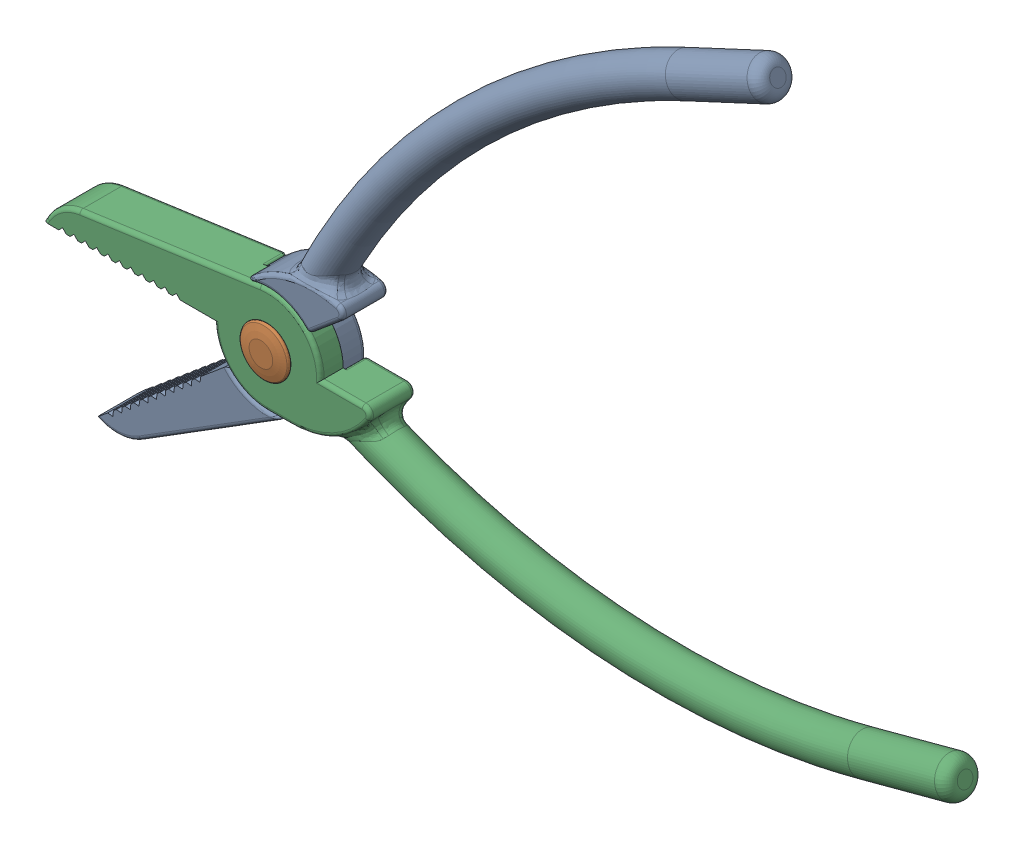
SolidWorks assembly 01_CSWA_Lvl9, configuration Default. Lengths in mm.
Overall size (243.58 187.01 15.4).
3 component instances, 3 part files, 5 mates.
Components (placement in the parent):
- Plier-Handle-1: Plier-Handle [Default] x (0.766044 0.642788 0) z (0 0 -1) size (237.62 44.74 12.21)
- Plier-Joint-1: Plier-Joint [Default] x (0.530011 0.847991 0) z (0 0 -1) size (13 13 15.4)
- Plier-Handle-Base-2: Plier-Handle-Base [Default] at origin size (237.62 44.74 12.21)
Mates (geometry in assembly coordinates):
- Coincident2: coincident anti-aligned: plane of Plier-Handle-1 through (0 0 -6) normal (0 0 -1); circle of Plier-Joint-1
- Concentric2: concentric aligned: cylinder of Plier-Handle-1 through (0 0 -6) axis (0 0 1) radius 3; cylinder of Plier-Joint-1 through (0 0 7.946) axis (0 0 1) radius 2.5
- Concentric5: concentric aligned: cylinder of Plier-Joint-1 through (0 0 7.946) axis (0 0 1) radius 2.5; circle of Plier-Handle-Base-2
- Coincident5: coincident anti-aligned: plane of Plier-Joint-1 through (0 0 6) normal (0 0 -1); plane of Plier-Handle-Base-2 through (0 0 6) normal (0 0 1)
- Angle2: planar angle = 0.698132 rad anti-aligned: plane of Plier-Handle-1 through (0 0 -6) normal (0.642788 -0.766044 0); plane of Plier-Handle-Base-2 through (0 0 6) normal (0 1 0)
